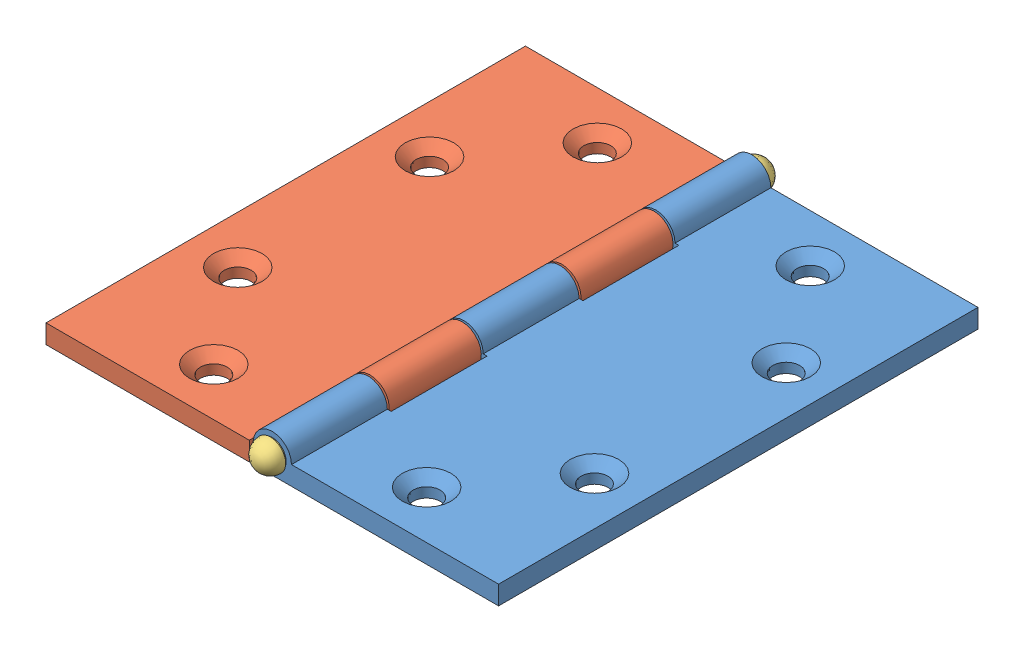
SolidWorks assembly hinge, configuration Default. Lengths in mm.
Overall size (119.89 10.21 136.14).
3 component instances, 3 part files, 8 mates.
Components (placement in the parent):
- Hinge 1-1: Hinge 1 [Default] at (36.068 5 -63.5) x (0 1 0) z (0 0 1) size (10.16 65.02 127)
- Hinge 2-1: Hinge 2 [Default] at (-23.876 5 -63.5) x (0 1 0) z (0 0 -1) size (10.16 65.02 127)
- hingepin-1: hingepin [Default] at (6.096 5 -63.5) x (0 0 -1) z (-0.952767 0.303702 0) size (136.14 8.13 8.13)
Mates (geometry in assembly coordinates):
- Concentric1: concentric anti-aligned: cylinder of Hinge 1-1 through (6.096 5 -121.8038) axis (0 0 1) radius 5.08; cylinder of Hinge 2-1 through (6.096 5 5.1962) axis (0 0 -1) radius 5.08
- Coincident1: coincident aligned: plane of Hinge 1-1 through (36.068 5 5.1962) normal (0 0 1); plane of Hinge 2-1 through (-23.876 5 5.1962) normal (0 0 1)
- Concentric2: concentric anti-aligned: cylinder of Hinge 2-1 through (6.096 5 5.1962) axis (0 0 -1) radius 5.08; cylinder of hingepin-1 through (6.096 5 -122.3118) axis (0 0 1) radius 3.175
- Width1: width aligned: plane of hingepin-1 through (6.096 5 -122.3118) normal (0 0 1); plane of hingepin-1 through (6.096 5 5.7042) normal (0 0 -1); plane of Hinge 1-1 through (36.068 5 5.1962) normal (0 0 1); plane of Hinge 1-1 through (36.068 5 -121.8038) normal (0 0 -1)
- Coincident2: coincident anti-aligned: plane of ? through (6.096 0 5.1962) normal (0 -1 0)
- Coincident3: coincident anti-aligned: plane of ? through (6.096 0 -121.8038) normal (0 -1 0)
- Coincident4: coincident aligned: plane of ? through (0 -0.08 -20.7118) normal (1 0 0)
- Coincident5: coincident aligned: plane of Hinge 2-1 through (-23.876 5 0) normal (0 0 1); plane of assembly
